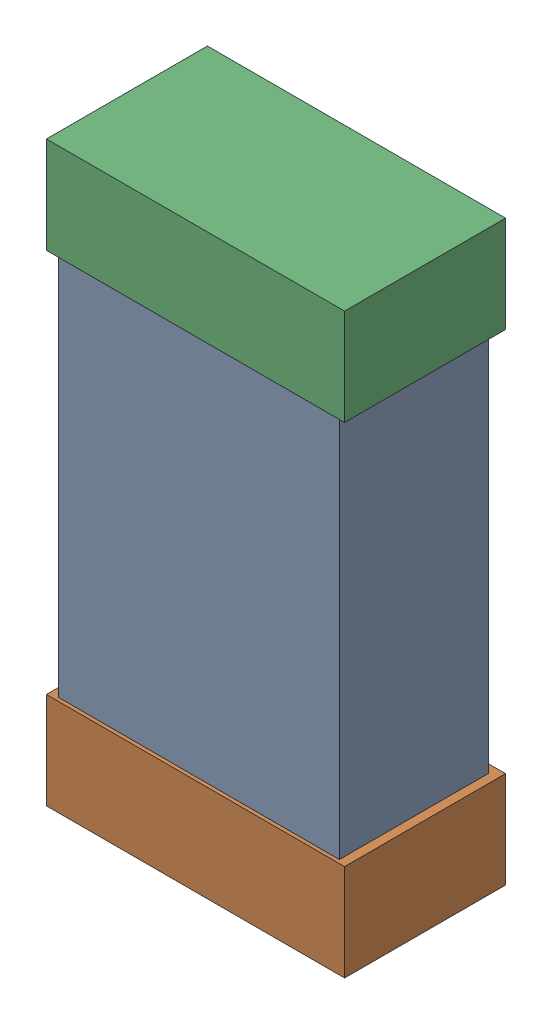
SolidWorks assembly R5, configuration Default. Lengths in mm.
Overall size (0.85 1.65 0.46).
6 component instances, 2 part files, 0 mates.
Components (placement in the parent):
- 432124816_44-1: 432124816_44 [Default] at (30.9457 22.0598 0.025) size (0.8 1.5 0.42)
  - Extruded (1)-1: Extruded (1) [Default] at origin size (0.8 1.5 0.42)
- 432138512_88-1: 432138512_88 [Default] at (30.9457 21.374 0.001) size (0.85 0.28 0.46)
  - Extruded-1: Extruded [Default] at origin size (0.85 0.28 0.46)
- 432138512_89-1: 432138512_89 [Default] at (30.9457 22.7456 0.001) size (0.85 0.28 0.46)
  - Extruded-1: Extruded [Default] at origin size (0.85 0.28 0.46)
